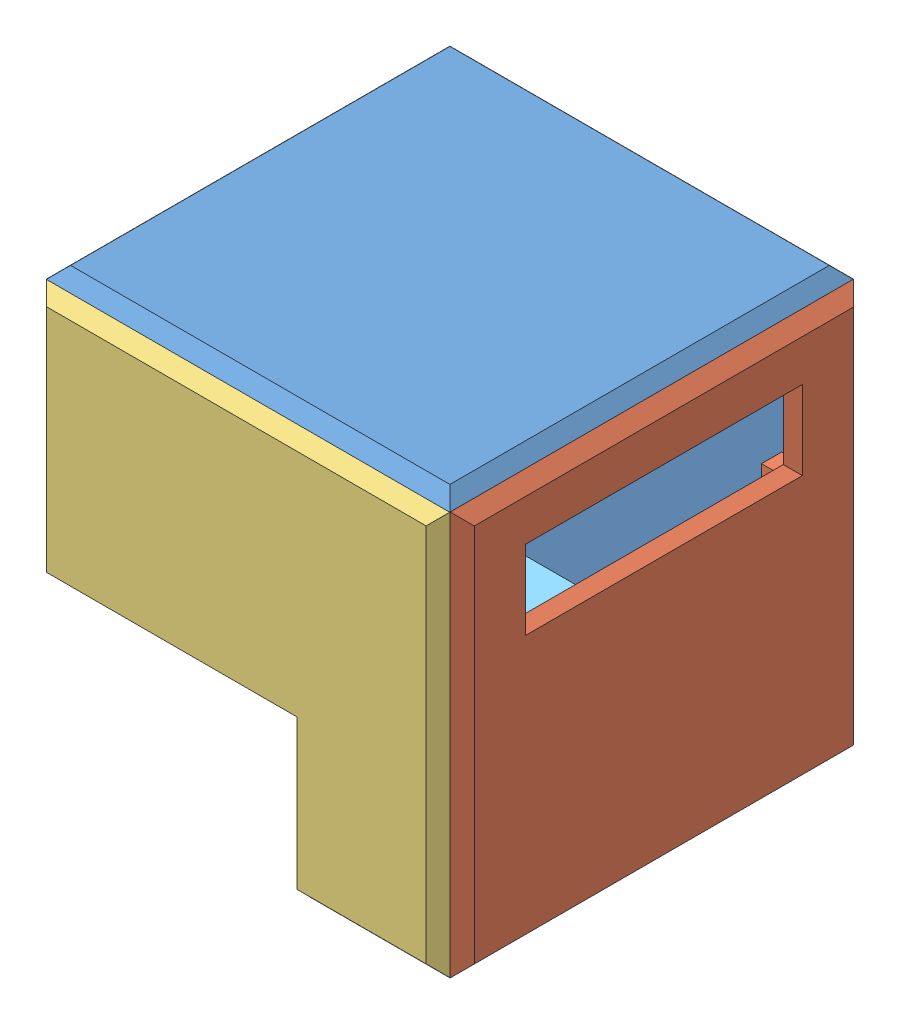
SolidWorks assembly petit_cube, configuration Défaut. Lengths in mm.
Overall size (106 105.95 105.9).
6 component instances, 5 part files, 17 mates.
Components (placement in the parent):
- cote_cubeh_1-1: cote_cubeh_1 [Défaut] at (-71.2157 -46.5017 93.5) size (100 100 13)
- Facade_lcd-1: Facade_lcd [Défaut] at (28.7843 -46.5017 196.45) x (0 0 -1) z (1 0 0) size (100 100 13)
- cote_cubeh_1-2: cote_cubeh_1 [Défaut] at (28.7843 56.4483 96.5038) x (0 0 1) z (0 -1 0) size (100 100 13)
- cote_cubeh_sym_mod-1: cote_cubeh_sym_mod [Défaut] at (-71.2157 -46.5017 193.4) size (100 100 13)
- cote_cubeh_back-1: cote_cubeh_back [Défaut] at (-74.2194 53.4983 196.45) x (0 -1 0) z (1 0 0) size (100 100 13)
- cote_cubeh_1_bot-1: cote_cubeh_1_bot [Défaut] at (28.7306 -49.5017 196.45) x (0 0 -1) z (0 1 0) size (100 100 13)
Mates (geometry in assembly coordinates):
- Coïncidente1: coincident anti-aligned: plane of cote_cubeh_1-1 through (-71.2157 -46.5017 96.5) normal (0 0 1); plane of Facade_lcd-1 through (18.7843 -6.5017 96.5) normal (0 0 -1)
- Coaxiale1: concentric aligned: cylinder of cote_cubeh_1-1 through (23.7343 53.4983 101.5) axis (0 -1 0) radius 1.525; cylinder of Facade_lcd-1 through (23.7343 -1.5017 101.5) axis (0 -1 0) radius 1.7
- Coïncidente2: coincident anti-aligned: plane of cote_cubeh_1-1 through (18.7343 -6.5017 106.5) normal (0 -1 0); plane of Facade_lcd-1 through (18.7843 -6.5017 96.5) normal (0 1 0)
- Parallèle1: parallel anti-aligned: plane of Facade_lcd-1 through (20.9343 48.4483 106.45) normal (0 1 0); plane of cote_cubeh_1-2 through (28.7843 53.4483 96.5038) normal (0 -1 0)
- Parallèle2: parallel aligned: line of Facade_lcd-1 through (28.7843 -46.5017 196.45) axis (0 0 -1); line of cote_cubeh_1-2 through (-71.2157 53.4483 196.5038) axis (0 0 -1)
- Coaxiale2: concentric aligned: cylinder of cote_cubeh_1-1 through (-16.2157 48.4483 101.55) axis (1 0 0) radius 1.75; cylinder of cote_cubeh_1-2 through (-71.2157 48.4483 101.55) axis (1 0 0) radius 1.525
- Coïncidente5: coincident anti-aligned: plane of cote_cubeh_1-1 through (-11.2157 53.4483 106.5) normal (-1 0 0); plane of cote_cubeh_1-2 through (-11.2157 43.4483 96.5538) normal (1 0 0)
- Coïncidente7: coincident anti-aligned: plane of cote_cubeh_1-2 through (-11.2157 43.4483 186.4538) normal (1 0 0); plane of cote_cubeh_sym_mod-1 through (-11.2157 53.4483 186.4) normal (-1 0 0)
- Coïncidente9: coincident anti-aligned: plane of Facade_lcd-1 through (18.7843 -6.5017 186.4) normal (0 1 0); plane of cote_cubeh_sym_mod-1 through (18.7343 -6.5017 186.4) normal (0 -1 0)
- Coaxiale6: concentric aligned: cylinder of Facade_lcd-1 through (23.7343 -1.5017 191.4) axis (0 -1 0) radius 1.7; cylinder of cote_cubeh_sym_mod-1 through (23.7343 53.4983 191.4) axis (0 -1 0) radius 1.525
- Coïncidente10: coincident anti-aligned: plane of cote_cubeh_1-1 through (-71.1657 -6.5017 106.5) normal (0 -1 0); plane of cote_cubeh_back-1 through (-61.2194 -6.5017 96.5) normal (0 1 0)
- Coaxiale7: concentric aligned: cylinder of cote_cubeh_1-1 through (-66.1694 53.4983 101.5) axis (0 -1 0) radius 1.525; cylinder of cote_cubeh_back-1 through (-66.1694 -1.5017 101.5) axis (0 -1 0) radius 1.75
- Parallèle3: parallel anti-aligned: plane of cote_cubeh_1-1 through (-71.1657 13.4983 106.5) normal (-1 0 0); plane of cote_cubeh_back-1 through (-71.2194 53.4983 196.45) normal (1 0 0)
- Parallèle4: parallel aligned: plane of cote_cubeh_back-1 through (-61.2194 -36.4517 126.4) normal (0 0 1); plane of cote_cubeh_1_bot-1 through (-71.2194 -36.5017 120.45) normal (0 0 1)
- Parallèle5: parallel anti-aligned: plane of cote_cubeh_sym_mod-1 through (-6.1657 -46.4517 186.4) normal (-1 0 0); plane of cote_cubeh_1_bot-1 through (4.7306 -36.5017 186.4) normal (1 0 0)
- Coaxiale9: concentric anti-aligned: cylinder of cote_cubeh_back-1 through (-66.2194 -41.4517 116.45) axis (0 0 1) radius 1.75; cylinder of cote_cubeh_1_bot-1 through (-66.2194 -41.4517 125.45) axis (0 0 -1) radius 1.525
- Coïncidente14: coincident anti-aligned: plane of cote_cubeh_sym_mod-1 through (-71.2157 -46.5017 196.4) normal (0 0 -1); plane of cote_cubeh_1_bot-1 through (4.7306 -36.5017 196.4) normal (0 0 1)
